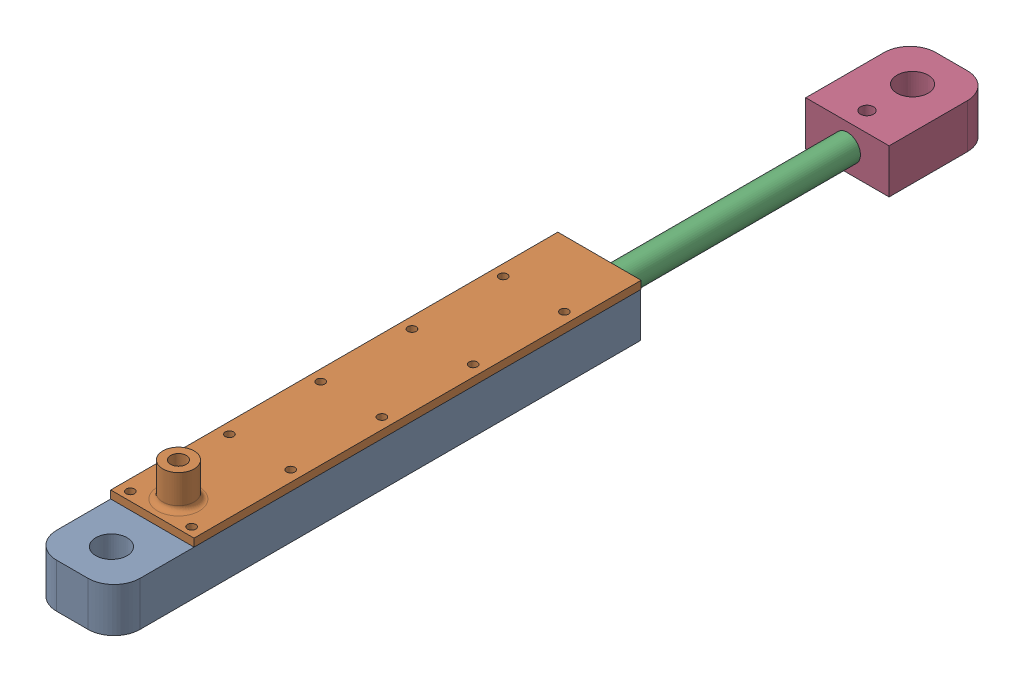
SolidWorks assembly Height_sensor_Assembly, configuration Default. Lengths in mm.
Overall size (32.1 33 337.46).
4 component instances, 4 part files, 6 mates.
Components (placement in the parent):
- Height_SensorV4.0P-1: Height_SensorV4.0P [Default] at origin size (32 17 202)
- Height_Sensor_Cover_V4.1-1: Height_Sensor_Cover_V4.1 [Default] at (0.004 24.5 161.293) x (0.000592 0 -1) z (1 0 0.000592) size (171.5 16 32)
- Height_Sensor_ShaftV4.0-1: Height_Sensor_ShaftV4.0 [Default] at (0 0 -110.4595) x (0.974643 0.223765 0) z (0 0 1) size (10 10 268.36)
- Height_Sensor_BottomV4.1P-1: Height_Sensor_BottomV4.1P [Default] at (0 -8.5 -115.4595) x (-1 0 0) z (0 0 -1) size (32 17 40)
Mates (geometry in assembly coordinates):
- Coincident1: coincident anti-aligned: plane of Height_SensorV4.0P-1 through (-16 8.5 3) normal (0 1 0); plane of Height_Sensor_Cover_V4.1-1 through (0.004 8.5 161.293) normal (0 -1 0)
- Concentric1: concentric aligned: cylinder of Height_SensorV4.0P-1 through (11.75 -37.5 168) axis (0 1 0) radius 2.1143; cylinder of Height_Sensor_Cover_V4.1-1 through (11.75 8.5 168) axis (0 1 0) radius 1.5875
- Concentric4: concentric aligned: cylinder of Height_SensorV4.0P-1 through (0 0 30.2) axis (0 0 -1) radius 4.25; cylinder of Height_Sensor_ShaftV4.0-1 through (0 0 157.9005) axis (0 0 -1) radius 3.75
- Coincident4: coincident anti-aligned: plane of Height_Sensor_ShaftV4.0-1 through (0 0 -110.4595) normal (0 0 -1); plane of Height_Sensor_BottomV4.1P-1 through (0 0 -110.4595) normal (0 0 1)
- Concentric7: concentric anti-aligned: cylinder of Height_Sensor_ShaftV4.0-1 through (0 0 -2.0995) axis (0 0 -1) radius 5; cylinder of Height_Sensor_BottomV4.1P-1 through (0 0 -110.4595) axis (0 0 1) radius 5
- Parallel1: parallel anti-aligned: plane of Height_Sensor_BottomV4.1P-1 through (6 -8.5 -125.4595) normal (0 -1 0)
